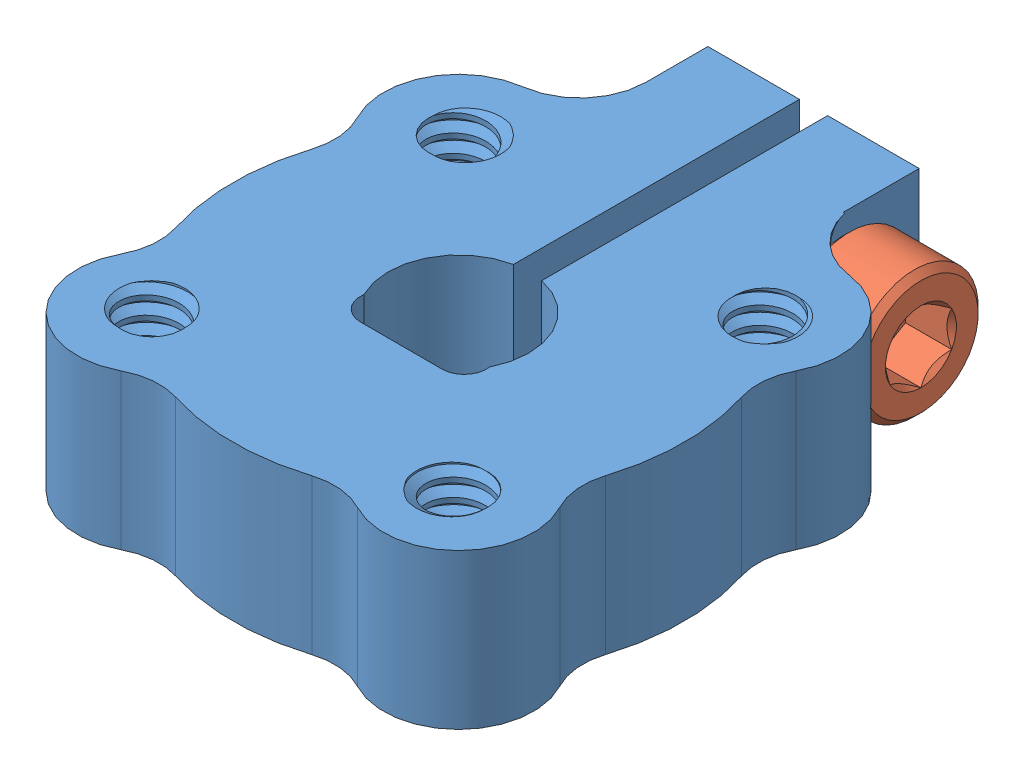
SolidWorks assembly servocity-hub-545619assembly, configuration Default. Lengths in mm.
Overall size (20.57 9.62 26.29).
2 component instances, 2 part files, 0 mates.
Components (placement in the parent):
- 545619-1: 545619 [Default] at (-37.8643 4.2066 16.6508) size (20.57 9.62 26.29)
- 632110_90128A121-1: 632110_90128A121 [Default] at (-42.6268 10.2391 4.0778) x (0 0 1) z (-1 0 0) size (5.74 5.74 13.19)
